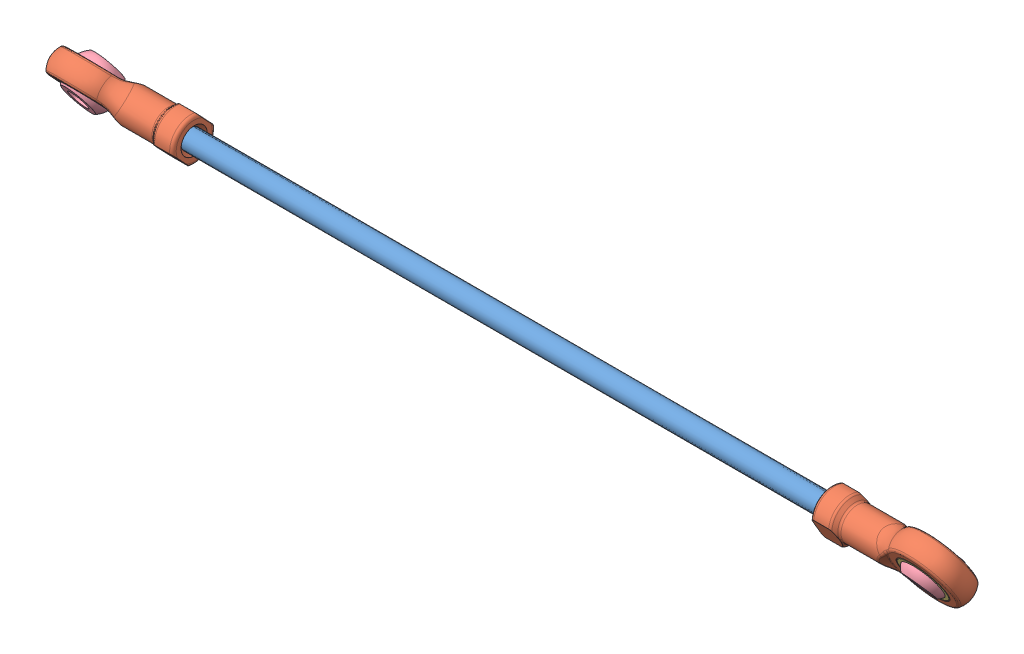
SolidWorks assembly Tie_rod_latest, configuration Default. Lengths in mm.
Overall size (139.32 12.63 12.16).
9 component instances, 4 part files, 4 mates.
Components (placement in the parent):
- shaft 1-1: shaft 1 [Default] at (89.9917 135.8608 189.9837) size (112.5 3 3)
- BallJoint Assy-1: BallJoint Assy [Default] at (63.8989 135.8608 189.9837) x (0 -0.728647 -0.68489) z (1 0 0) size (10.82 6.52 21)
  - Body-1: Body [Default] at origin size (10.82 5.6 21)
  - Liner-1: Liner [Default] at (0 0 18.0928) x (0.47258 0 0.881288) z (-0.881288 0 0.47258) size (7.88 3.5 7.88)
  - Ball-1: Ball [Default] at (0 0 18.0928) x (0.766515 -0.174296 0.618122) z (-0.619213 0.054765 0.783311) size (7 5 7)
- BallJoint Assy-2: BallJoint Assy [Default] at (228.5846 135.8608 189.9837) x (0 -0.862425 -0.506184) z (-1 0 0) size (10.82 6.52 21)
  - Body-1: Body [Default] at origin size (10.82 5.6 21)
  - Liner-1: Liner [Default] at (0 0 18.0928) x (0.47258 0 0.881288) z (-0.881288 0 0.47258) size (7.88 3.5 7.88)
  - Ball-1: Ball [Default] at (0 0 18.0928) x (0.766515 -0.174296 0.618122) z (-0.619213 0.054765 0.783311) size (7 5 7)
Mates (geometry in assembly coordinates):
- Concentric13: concentric aligned: cylinder of shaft 1-1 through (202.4917 135.8608 189.9837) axis (-1 0 0) radius 1.5; cylinder of BallJoint Assy-2/Body-1 through (202.4917 135.8608 189.9837) axis (-1 0 0) radius 1.5
- Coincident3: coincident anti-aligned: plane of shaft 1-1 through (202.4917 135.8608 189.9837) normal (1 0 0); plane of BallJoint Assy-2/Body-1 through (202.4917 135.8608 189.9837) normal (-1 0 0)
- Coincident4: coincident anti-aligned: plane of shaft 1-1 through (89.9917 135.8608 189.9837) normal (-1 0 0); plane of BallJoint Assy-1/Body-1 through (89.9917 135.8608 189.9837) normal (1 0 0)
- Concentric15: concentric anti-aligned: cylinder of shaft 1-1 through (202.4917 135.8608 189.9837) axis (-1 0 0) radius 1.5; cylinder of BallJoint Assy-1/Body-1 through (89.9917 135.8608 189.9837) axis (1 0 0) radius 1.5
